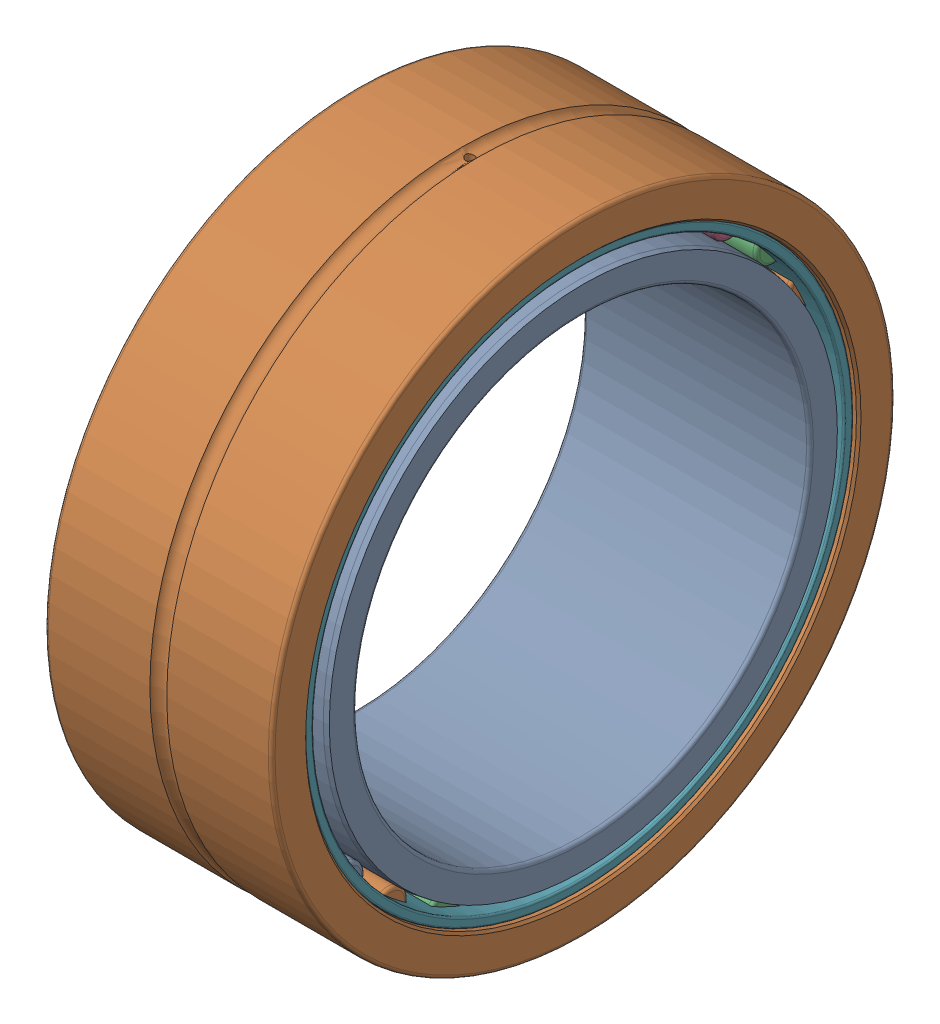
SolidWorks assembly NK45_20R+IR40x45x20, configuration Default. Lengths in mm.
Overall size (20 55 55).
31 component instances, 4 part files, 0 mates.
Components (placement in the parent):
- NK45_20R+IR40x45x20Inner ring-1: NK45_20R+IR40x45x20Inner ring [Default] at origin size (20 45 45)
- NK45_20R+IR40x45x20Outer ring-1: NK45_20R+IR40x45x20Outer ring [Default] at origin size (20 55 55)
- NK45_20R+IR40x45x20 ring-1: NK45_20R+IR40x45x20 ring [Default] at (2 24 0) size (16 3 3)
- NK45_20R+IR40x45x20 ring-2: NK45_20R+IR40x45x20 ring [Default] at (2 23.3983 5.3405) size (16 3 3)
- NK45_20R+IR40x45x20 ring-3: NK45_20R+IR40x45x20 ring [Default] at (2 21.6233 10.4132) size (16 3 3)
- NK45_20R+IR40x45x20 ring-4: NK45_20R+IR40x45x20 ring [Default] at (2 18.764 14.9638) size (16 3 3)
- NK45_20R+IR40x45x20 ring-5: NK45_20R+IR40x45x20 ring [Default] at (2 14.9638 18.764) size (16 3 3)
- NK45_20R+IR40x45x20 ring-6: NK45_20R+IR40x45x20 ring [Default] at (2 10.4132 21.6233) size (16 3 3)
- NK45_20R+IR40x45x20 ring-7: NK45_20R+IR40x45x20 ring [Default] at (2 5.3405 23.3983) size (16 3 3)
- NK45_20R+IR40x45x20 ring-8: NK45_20R+IR40x45x20 ring [Default] at (2 0 24) size (16 3 3)
- NK45_20R+IR40x45x20 ring-9: NK45_20R+IR40x45x20 ring [Default] at (2 -5.3405 23.3983) size (16 3 3)
- NK45_20R+IR40x45x20 ring-10: NK45_20R+IR40x45x20 ring [Default] at (2 -10.4132 21.6233) size (16 3 3)
- NK45_20R+IR40x45x20 ring-11: NK45_20R+IR40x45x20 ring [Default] at (2 -14.9638 18.764) size (16 3 3)
- NK45_20R+IR40x45x20 ring-12: NK45_20R+IR40x45x20 ring [Default] at (2 -18.764 14.9638) size (16 3 3)
- NK45_20R+IR40x45x20 ring-13: NK45_20R+IR40x45x20 ring [Default] at (2 -21.6233 10.4132) size (16 3 3)
- NK45_20R+IR40x45x20 ring-14: NK45_20R+IR40x45x20 ring [Default] at (2 -23.3983 5.3405) size (16 3 3)
- NK45_20R+IR40x45x20 ring-15: NK45_20R+IR40x45x20 ring [Default] at (2 -24 0) size (16 3 3)
- NK45_20R+IR40x45x20 ring-16: NK45_20R+IR40x45x20 ring [Default] at (2 -23.3983 -5.3405) size (16 3 3)
- NK45_20R+IR40x45x20 ring-17: NK45_20R+IR40x45x20 ring [Default] at (2 -21.6233 -10.4132) size (16 3 3)
- NK45_20R+IR40x45x20 ring-18: NK45_20R+IR40x45x20 ring [Default] at (2 -18.764 -14.9638) size (16 3 3)
- NK45_20R+IR40x45x20 ring-19: NK45_20R+IR40x45x20 ring [Default] at (2 -14.9638 -18.764) size (16 3 3)
- NK45_20R+IR40x45x20 ring-20: NK45_20R+IR40x45x20 ring [Default] at (2 -10.4132 -21.6233) size (16 3 3)
- NK45_20R+IR40x45x20 ring-21: NK45_20R+IR40x45x20 ring [Default] at (2 -5.3405 -23.3983) size (16 3 3)
- NK45_20R+IR40x45x20 ring-22: NK45_20R+IR40x45x20 ring [Default] at (2 0 -24) size (16 3 3)
- NK45_20R+IR40x45x20 ring-23: NK45_20R+IR40x45x20 ring [Default] at (2 5.3405 -23.3983) size (16 3 3)
- NK45_20R+IR40x45x20 ring-24: NK45_20R+IR40x45x20 ring [Default] at (2 10.4132 -21.6233) size (16 3 3)
- NK45_20R+IR40x45x20 ring-25: NK45_20R+IR40x45x20 ring [Default] at (2 14.9638 -18.764) size (16 3 3)
- NK45_20R+IR40x45x20 ring-26: NK45_20R+IR40x45x20 ring [Default] at (2 18.764 -14.9638) size (16 3 3)
- NK45_20R+IR40x45x20 ring-27: NK45_20R+IR40x45x20 ring [Default] at (2 21.6233 -10.4132) size (16 3 3)
- NK45_20R+IR40x45x20 ring-28: NK45_20R+IR40x45x20 ring [Default] at (2 23.3983 -5.3405) size (16 3 3)
- NK45_20R+IR40x45x20Cage-1: NK45_20R+IR40x45x20Cage [Default] at origin size (19.2 48.5 48.5)
